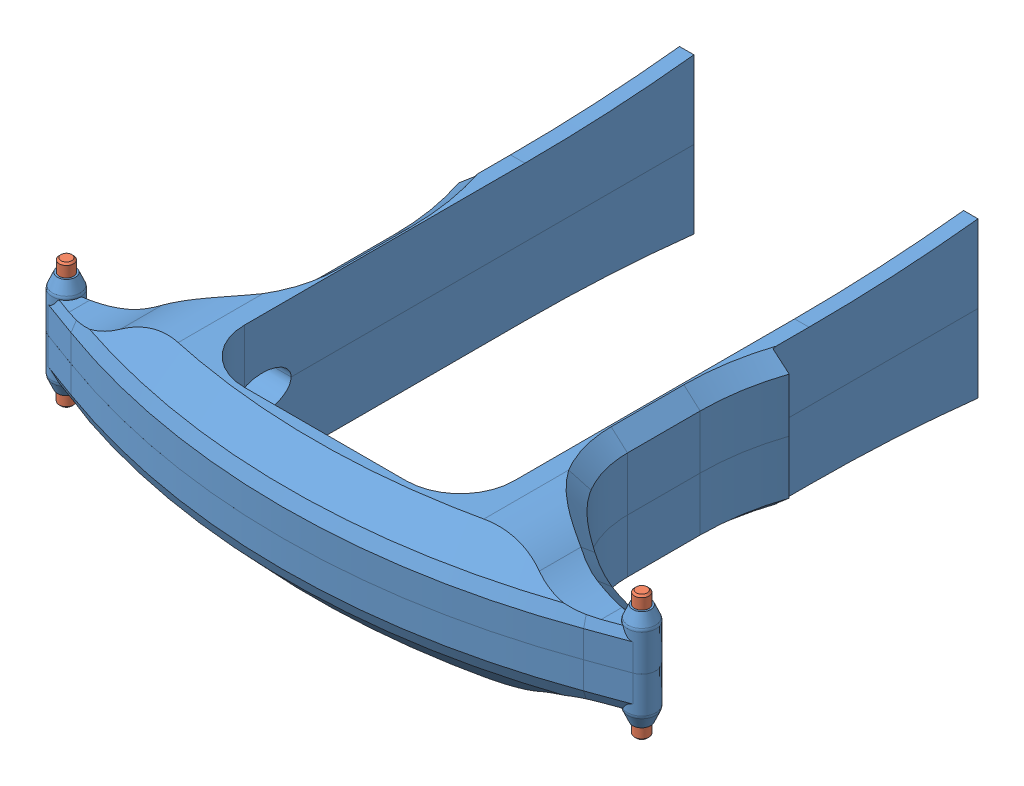
SolidWorks assembly Rahmen-Vorne, configuration Standard. Lengths in mm.
Overall size (168.02 43.2 152).
4 component instances, 2 part files, 6 mates.
Components (placement in the parent):
- Rahmen-Vorne-1: Rahmen-Vorne [Standard] at origin size (168 22.26 152)
- Achse 4mm-1: Achse 4mm [L=35] at (-80 0 0) x (0 -1 0) z (-1 0 0) size (35 4 4)
- Rahmen-Vorne-2: Rahmen-Vorne [Standard] at (-0.0168 0 0) x (-1 0 0) z (0 0 1) size (168 22.26 152)
- Achse 4mm-2: Achse 4mm [L=35] at (80 0 0) x (0 -1 0) z (-1 0 0) size (35 4 4)
Mates (geometry in assembly coordinates):
- Deckungsgleich1: coincident aligned: plane of Rahmen-Vorne-1 through (0 0 0) normal (1 0 0); plane of assembly through (0 0 0) normal (1 0 0)
- Deckungsgleich2: coincident aligned: plane of Rahmen-Vorne-1 through (0 0 0) normal (0 1 0); plane of assembly through (0 0 0) normal (0 1 0)
- Deckungsgleich3: coincident aligned: plane of Rahmen-Vorne-1 through (0 0 0) normal (0 0 1); plane of assembly through (0 0 0) normal (0 0 1)
- Konzentrisch1: concentric anti-aligned: cylinder of Rahmen-Vorne-1 through (-80 19 0) axis (0 -1 0) radius 2; cylinder of Achse 4mm-1 through (-80 -17.5 0) axis (0 1 0) radius 2
- Deckungsgleich4: coincident anti-aligned: plane of Achse 4mm-1; plane of assembly through (0 0 0) normal (0 1 0)
- Deckungsgleich5: coincident aligned: plane of Achse 4mm-1; plane of assembly through (0 0 0) normal (0 0 1)
